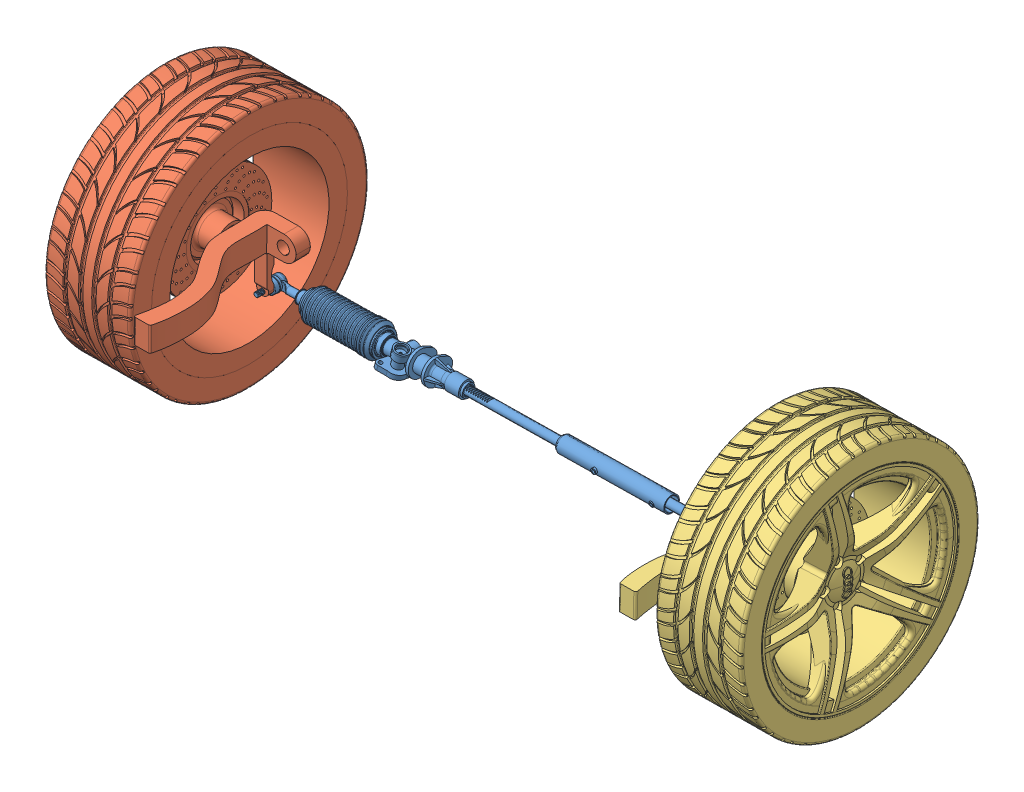
SolidWorks assembly Assem13, configuration Default. Lengths in mm.
Overall size (1993.98 692.3 723.83).
3 component instances, 3 part files, 4 mates.
Components (placement in the parent):
- Tie_rod_components_lastly-1: Tie_rod_components_lastly [Default] at origin size (1517.72 93.25 111.55)
- left_wheel_ver2-1: left_wheel_ver2 [Default] at (-272.5066 135.6031 98.2437) x (0.999957 0.000058 -0.009269) z (0.009268 0.00842 0.999922) size (361.62 668.92 691.48)
- right_wheel_ver2-1: right_wheel_ver2 [Default] at (1174.1858 146.8488 82.3617) x (0.999958 -0.000025 -0.009154) z (0.009151 0.026402 0.99961) size (361.62 668.92 691.48)
Mates (geometry in assembly coordinates):
- Concentric1: concentric: cylinder of Tie_rod_components_lastly-1 through (-289.9747 -1.8908 19.9872) axis (-0.009269 0.002009 -0.999955) radius 6.4528; cylinder of left_wheel_ver2-1 through (-290.0759 -1.8688 9.0715) axis (0.009269 -0.002009 0.999955) radius 6
- Coincident1: coincident anti-aligned: plane of Tie_rod_components_lastly-1 through (-289.9598 4.5498 26.0547) normal (0.009269 -0.002009 0.999955); plane of left_wheel_ver2-1 through (-306.6676 -10.9412 26.1784) normal (-0.009269 0.002009 -0.999955)
- Concentric2: concentric: cylinder of Tie_rod_components_lastly-1 through (1190.2365 7.8893 6.2832) axis (-0.009153 -0.015975 -0.99983) radius 6.4528; cylinder of right_wheel_ver2-1 through (1190.1366 7.7149 -4.6312) axis (0.009153 0.015975 0.99983) radius 6
- Coincident2: coincident anti-aligned: plane of Tie_rod_components_lastly-1 through (1190.3342 1.5342 12.4392) normal (0.009153 0.015975 0.99983); plane of right_wheel_ver2-1 through (1207.0411 8.8118 12.17) normal (-0.009153 -0.015975 -0.99983)
